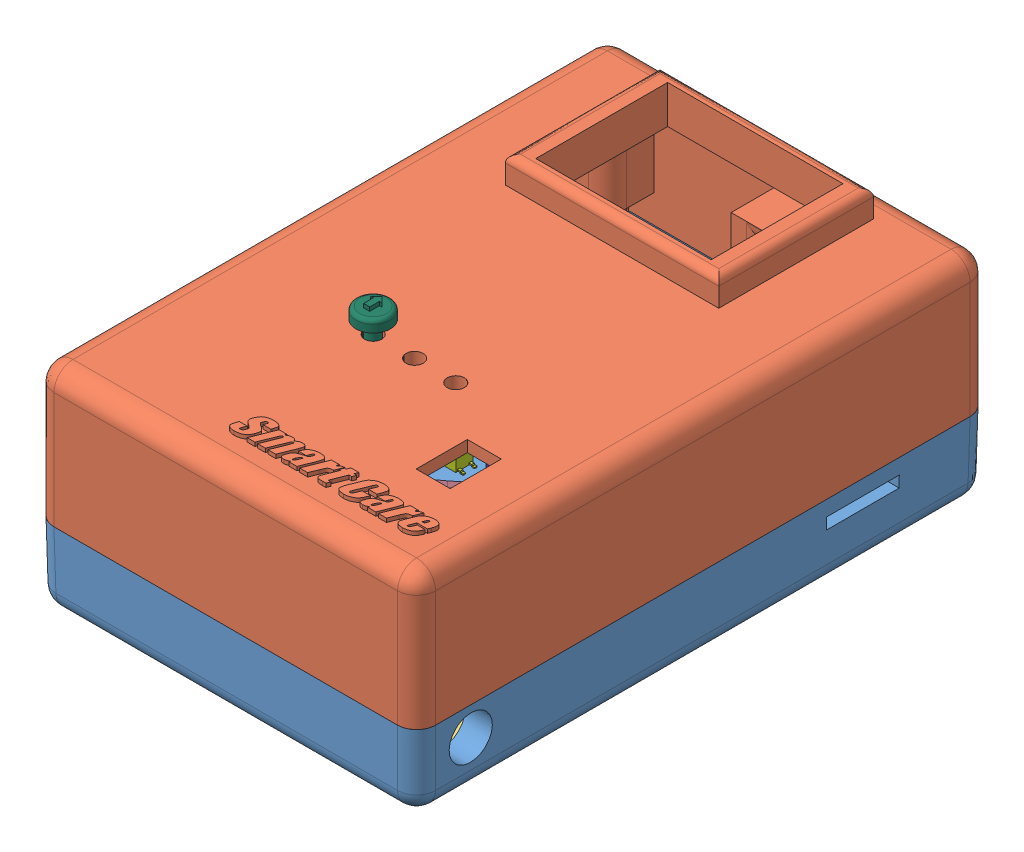
SolidWorks assembly Assem1, configuration Default. Lengths in mm.
Overall size (107.55 70.38 150.1).
258 component instances, 87 part files, 2 mates.
Components (placement in the parent):
- Bottom-1: Bottom [Default] at (52.2963 76.6839 118.1706) size (107.5 43.17 150)
- Top-1: Top [Default] at origin size (100.1 59.21 150.1)
- battery closing-1: battery closing [Default] at origin size (83.47 2 79.99)
- PCB1.step-1: PCB1.step [Default] at (13.8153 94.0015 157.6572) x (1 0 0) z (0 1 0) size (76.65 69.31 14.5)
  - Board.step-1: Board.step [Default] at origin size (76.65 68.06 1.61)
    - Open CASCADE STEP translator 7.5 1.1.1.step-1: Open CASCADE STEP translator 7.5 1.1.1.step [Default] at (0 0 -1.6065) size (76.65 68.06 1.61)
  - SD.step-1: SD.step [Default] at origin size (10.5 3.5 7.2)
    - 6598036848.step-1: 6598036848.step [Default] at (20.962 62.865 0) x (1 0 0) z (0 0 1) size (10.5 3.5 7.2)
      - Body.step-1: Body.step [Default] at origin size (10.5 3.5 4.5)
      - LeadsArray.step-1: LeadsArray.step [Default] at origin size (8 0.5 7.2)
  - Right.step-1: Right.step [Default] at origin size (7.5 4.5 5)
    - 6598039168.step-1: 6598039168.step [Default] at (48.895 14.351 0) x (-1 0 0) z (0 1 0) size (7.5 5 4.5)
  - r9.step-1: r9.step [Default] at origin size (2 1.25 0.6)
    - 6598044208.step-1: 6598044208.step [Default] at (71.247 35.052 0) x (1 0 0) z (0 0 1) size (2 1.25 0.6)
      - solidBody.step-1: solidBody.step [Default] at origin size (2 1.24 0.5)
      - Terminal.step-1: Terminal.step [Default] at origin size (2 1.25 0.6)
      - solidTop.step-1: solidTop.step [Default] at origin size (1.2 1 0.05)
  - r8.step-1: r8.step [Default] at origin size (2 1.25 0.6)
    - 6598044208.step-1: 6598044208.step [Default] at (66.294 35.052 0) x (1 0 0) z (0 0 1) size (2 1.25 0.6)
      - solidBody.step-1: solidBody.step [Default] at origin size (2 1.24 0.5)
      - Terminal.step-1: Terminal.step [Default] at origin size (2 1.25 0.6)
      - solidTop.step-1: solidTop.step [Default] at origin size (1.2 1 0.05)
  - r7.step-1: r7.step [Default] at origin size (2 1.25 0.6)
    - 6598047408.step-1: 6598047408.step [Default] at (23.622 43.688 0) size (2 1.25 0.6)
      - solidBody-0.step-1: solidBody-0.step [Default] at origin size (2 1.24 0.5)
      - Terminal-1.step-1: Terminal-1.step [Default] at origin size (2 1.25 0.6)
      - solidTop-2.step-1: solidTop-2.step [Default] at origin size (1.2 1 0.05)
  - r6.step-1: r6.step [Default] at origin size (2 1.25 0.6)
    - 6598034208.step-1: 6598034208.step [Default] at (18.288 43.688 0) x (-1 0 0) z (0 0 1) size (2 1.25 0.6)
      - solidBody-3.step-1: solidBody-3.step [Default] at origin size (2 1.24 0.5)
      - Terminal-4.step-1: Terminal-4.step [Default] at origin size (2 1.25 0.6)
      - solidTop-5.step-1: solidTop-5.step [Default] at origin size (1.2 1 0.05)
  - r5.step-1: r5.step [Default] at origin size (2 1.25 0.6)
    - 6598034208.step-1: 6598034208.step [Default] at (28.099 39.116 0) x (-1 0 0) z (0 0 1) size (2 1.25 0.6)
      - solidBody-3.step-1: solidBody-3.step [Default] at origin size (2 1.24 0.5)
      - Terminal-4.step-1: Terminal-4.step [Default] at origin size (2 1.25 0.6)
      - solidTop-5.step-1: solidTop-5.step [Default] at origin size (1.2 1 0.05)
  - r4.step-1: r4.step [Default] at origin size (2 1.25 0.6)
    - 6598034208.step-1: 6598034208.step [Default] at (50.673 49.149 -1.6065) x (-1 0 0) z (0 0 -1) size (2 1.25 0.6)
      - solidBody-3.step-1: solidBody-3.step [Default] at origin size (2 1.24 0.5)
      - Terminal-4.step-1: Terminal-4.step [Default] at origin size (2 1.25 0.6)
      - solidTop-5.step-1: solidTop-5.step [Default] at origin size (1.2 1 0.05)
  - r3.step-1: r3.step [Default] at origin size (2 1.25 0.6)
    - 6598034208.step-1: 6598034208.step [Default] at (50.673 51.308 -1.6065) x (-1 0 0) z (0 0 -1) size (2 1.25 0.6)
      - solidBody-3.step-1: solidBody-3.step [Default] at origin size (2 1.24 0.5)
      - Terminal-4.step-1: Terminal-4.step [Default] at origin size (2 1.25 0.6)
      - solidTop-5.step-1: solidTop-5.step [Default] at origin size (1.2 1 0.05)
  - r2.step-1: r2.step [Default] at origin size (2 1.25 0.6)
    - 6598034208.step-1: 6598034208.step [Default] at (50.673 53.594 -1.6065) x (-1 0 0) z (0 0 -1) size (2 1.25 0.6)
      - solidBody-3.step-1: solidBody-3.step [Default] at origin size (2 1.24 0.5)
      - Terminal-4.step-1: Terminal-4.step [Default] at origin size (2 1.25 0.6)
      - solidTop-5.step-1: solidTop-5.step [Default] at origin size (1.2 1 0.05)
  - r1.step-1: r1.step [Default] at origin size (2 1.25 0.6)
    - 6598034208.step-1: 6598034208.step [Default] at (62.611 46.355 -1.6065) x (-1 0 0) z (0 0 -1) size (2 1.25 0.6)
      - solidBody-3.step-1: solidBody-3.step [Default] at origin size (2 1.24 0.5)
      - Terminal-4.step-1: Terminal-4.step [Default] at origin size (2 1.25 0.6)
      - solidTop-5.step-1: solidTop-5.step [Default] at origin size (1.2 1 0.05)
  - Power.step-1: Power.step [Default] at origin size (9.4 14.4 14.5)
    - 6598038208.step-1: 6598038208.step [Default] at (60.325 22.564 5.5) x (0 -1 0) z (-1 0 0) size (14.4 14.5 9.4)
  - On_Off.step-1: On_Off.step [Default] at origin size (5.9 4.5 9.4)
    - 6598040288.step-1: 6598040288.step [Default] at (50.562 28.406 2.91) x (1 0 0) z (0 -1 0) size (5.9 9.4 4.5)
  - Left.step-1: Left.step [Default] at origin size (7.5 4.5 5)
    - 6598039168.step-1: 6598039168.step [Default] at (27.095 14.502 0) x (-1 0 0) z (0 1 0) size (7.5 5 4.5)
  - J1.step-1: J1.step [Default] at origin size (6.75 8.95 4.17)
    - Conn_Molex_2171790001_eec.step-1: Conn_Molex_2171790001_eec.step [Default] at (73.406 43.815 0) x (0 1 0) z (0 0 1) size (8.95 6.75 4.17)
      - A1.step-1: A1.step [Default] at (-0.0001 0.125 1.5815) x (-1 0 0) z (0 1 0) size (8.95 4.17 6.75)
        - 1.step-1: 1.step [Default] at origin size (5.77 0.7 2.37)
        - 2.step-1: 2.step [Default] at origin size (6.69 0.16 2.46)
        - 3.step-1: 3.step [Default] at origin size (6.85 0.12 0.59)
        - 4.step-1: 4.step [Default] at origin size (3.83 0.9 0.61)
        - 5.step-1: 5.step [Default] at origin size (8.29 2.9 0.65)
        - 6.step-1: 6.step [Default] at origin size (8.29 2.62 0.59)
        - 7.step-1: 7.step [Default] at origin size (4.77 2.56 0.5)
        - 8.step-1: 8.step [Default] at origin size (8.29 2.49 5.77)
        - 9.step-1: 9.step [Default] at origin size (8.95 4.17 6.5)
      - Notch.step-1: Notch.step [Default] at (2.989 3.252 0.0996) x (1 0 0) z (0 -1 0) size (0.16 0.12 0)
      - Molex.step-1: Molex.step [Default] at (0.4529 0.8873 3.359) size (1.82 0.45 0)
  - IC2.step-1: IC2.step [Default] at origin size (18 25.5 3.25)
    - 6598038368.step-1: 6598038368.step [Default] at (38.454 56.936 0) x (1 0 0) z (0 -1 0) size (18 3.25 25.5)
  - Enter.step-1: Enter.step [Default] at origin size (7.5 4.5 5)
    - 6598039168.step-1: 6598039168.step [Default] at (37.973 14.478 0) x (-1 0 0) z (0 1 0) size (7.5 5 4.5)
  - EN.step-1: EN.step [Default] at origin size (4.5 7.5 5)
    - 6598042848.step-1: 6598042848.step [Default] at (22.479 52.324 0) x (0 1 0) z (1 0 0) size (7.5 5 4.5)
  - ECG.step-1: ECG.step [Default] at origin size (10.5 3.5 7.2)
    - 6598036848.step-1: 6598036848.step [Default] at (62.158 63.627 0) x (1 0 0) z (0 0 1) size (10.5 3.5 7.2)
      - Body.step-1: Body.step [Default] at origin size (10.5 3.5 4.5)
      - LeadsArray.step-1: LeadsArray.step [Default] at origin size (8 0.5 7.2)
  - TFT.step-1: TFT.step [Default] at origin size (6.4 22.5 12.2)
    - 6598036528.step-1: 6598036528.step [Default] at (7.493 54.838 0) x (0 1 0) z (0 0 1) size (22.5 6.4 12.2)
      - Body-6.step-1: Body-6.step [Default] at origin size (22.5 6.4 8.8)
      - LeadsArray-7.step-1: LeadsArray-7.step [Default] at origin size (18.1 0.6 12.2)
  - D4.step-1: D4.step [Default] at origin size (1.07 0.68 0.43)
    - 6598042608.step-1: 6598042608.step [Default] at (66.873 37.973 0.01) x (1 0 0) z (0 -1 0) size (1.07 0.43 0.68)
  - D3.step-1: D3.step [Default] at origin size (1.07 0.68 0.43)
    - 6598042608.step-1: 6598042608.step [Default] at (66.802 40.64 0.01) x (1 0 0) z (0 -1 0) size (1.07 0.43 0.68)
  - D2.step-1: D2.step [Default] at origin size (1.07 0.68 0.43)
    - 6598042608.step-1: 6598042608.step [Default] at (66.802 42.926 0.01) x (1 0 0) z (0 -1 0) size (1.07 0.43 0.68)
  - D1.step-1: D1.step [Default] at origin size (1.07 0.68 0.43)
    - 6598042608.step-1: 6598042608.step [Default] at (66.675 45.085 0.01) x (1 0 0) z (0 -1 0) size (1.07 0.43 0.68)
  - c20.step-1: c20.step [Default] at origin size (2 1.25 1.4)
    - 6598033648.step-1: 6598033648.step [Default] at (46.99 39.497 0) x (-1 0 0) z (0 0 1) size (2 1.25 1.4)
      - Fillet1.step-1: Fillet1.step [Default] at origin size (0.5 1.25 1.4)
      - Fillet2.step-1: Fillet2.step [Default] at origin size (0.5 1.25 1.4)
      - body2.step-1: body2.step [Default] at origin size (1 1.22 1.37)
  - c19.step-1: c19.step [Default] at origin size (2 1.25 1.4)
    - 6598033648.step-1: 6598033648.step [Default] at (32.385 7.874 0) x (-1 0 0) z (0 0 1) size (2 1.25 1.4)
      - Fillet1.step-1: Fillet1.step [Default] at origin size (0.5 1.25 1.4)
      - Fillet2.step-1: Fillet2.step [Default] at origin size (0.5 1.25 1.4)
      - body2.step-1: body2.step [Default] at origin size (1 1.22 1.37)
  - c18.step-1: c18.step [Default] at origin size (2 1.25 1.4)
    - 6598033648.step-1: 6598033648.step [Default] at (44.069 7.874 0) x (-1 0 0) z (0 0 1) size (2 1.25 1.4)
      - Fillet1.step-1: Fillet1.step [Default] at origin size (0.5 1.25 1.4)
      - Fillet2.step-1: Fillet2.step [Default] at origin size (0.5 1.25 1.4)
      - body2.step-1: body2.step [Default] at origin size (1 1.22 1.37)
  - c17.step-1: c17.step [Default] at origin size (2 1.25 1.4)
    - 6598033648.step-1: 6598033648.step [Default] at (38.354 8.001 0) x (-1 0 0) z (0 0 1) size (2 1.25 1.4)
      - Fillet1.step-1: Fillet1.step [Default] at origin size (0.5 1.25 1.4)
      - Fillet2.step-1: Fillet2.step [Default] at origin size (0.5 1.25 1.4)
      - body2.step-1: body2.step [Default] at origin size (1 1.22 1.37)
  - c16.step-1: c16.step [Default] at origin size (2 1.25 1.4)
    - 6598043008.step-1: 6598043008.step [Default] at (16.383 54.229 0) x (1 0 0) z (0 0 1) size (2 1.25 1.4)
      - Fillet1-8.step-1: Fillet1-8.step [Default] at origin size (0.5 1.25 1.4)
      - Fillet2-9.step-1: Fillet2-9.step [Default] at origin size (0.5 1.25 1.4)
      - body2-10.step-1: body2-10.step [Default] at origin size (1 1.22 1.37)
  - c15.step-1: c15.step [Default] at origin size (2 1.25 1.4)
    - 6598043008.step-1: 6598043008.step [Default] at (31.28 21.717 0) x (1 0 0) z (0 0 1) size (2 1.25 1.4)
      - Fillet1-8.step-1: Fillet1-8.step [Default] at origin size (0.5 1.25 1.4)
      - Fillet2-9.step-1: Fillet2-9.step [Default] at origin size (0.5 1.25 1.4)
      - body2-10.step-1: body2-10.step [Default] at origin size (1 1.22 1.37)
  - c14.step-1: c14.step [Default] at origin size (2 1.25 1.4)
    - 6598043008.step-1: 6598043008.step [Default] at (26.454 21.463 0) x (1 0 0) z (0 0 1) size (2 1.25 1.4)
      - Fillet1-8.step-1: Fillet1-8.step [Default] at origin size (0.5 1.25 1.4)
      - Fillet2-9.step-1: Fillet2-9.step [Default] at origin size (0.5 1.25 1.4)
      - body2-10.step-1: body2-10.step [Default] at origin size (1 1.22 1.37)
  - c13.step-1: c13.step [Default] at origin size (2 1.25 1.4)
    - 6598033648.step-1: 6598033648.step [Default] at (42.291 22.098 0) x (-1 0 0) z (0 0 1) size (2 1.25 1.4)
      - Fillet1.step-1: Fillet1.step [Default] at origin size (0.5 1.25 1.4)
      - Fillet2.step-1: Fillet2.step [Default] at origin size (0.5 1.25 1.4)
      - body2.step-1: body2.step [Default] at origin size (1 1.22 1.37)
  - c12.step-1: c12.step [Default] at origin size (1.25 2 1.4)
    - 6598039248.step-1: 6598039248.step [Default] at (33.909 29.68 0) x (0 -1 0) z (0 0 1) size (2 1.25 1.4)
      - Fillet1-11.step-1: Fillet1-11.step [Default] at origin size (0.5 1.25 1.4)
      - Fillet2-12.step-1: Fillet2-12.step [Default] at origin size (0.5 1.25 1.4)
      - body2-13.step-1: body2-13.step [Default] at origin size (1 1.22 1.37)
  - c11.step-1: c11.step [Default] at origin size (2 1.25 1.4)
    - 6598043008.step-1: 6598043008.step [Default] at (37.503 21.844 0) x (1 0 0) z (0 0 1) size (2 1.25 1.4)
      - Fillet1-8.step-1: Fillet1-8.step [Default] at origin size (0.5 1.25 1.4)
      - Fillet2-9.step-1: Fillet2-9.step [Default] at origin size (0.5 1.25 1.4)
      - body2-10.step-1: body2-10.step [Default] at origin size (1 1.22 1.37)
  - c10.step-1: c10.step [Default] at origin size (2 1.25 1.4)
    - 6598033648.step-1: 6598033648.step [Default] at (42.075 39.497 0) x (-1 0 0) z (0 0 1) size (2 1.25 1.4)
      - Fillet1.step-1: Fillet1.step [Default] at origin size (0.5 1.25 1.4)
      - Fillet2.step-1: Fillet2.step [Default] at origin size (0.5 1.25 1.4)
      - body2.step-1: body2.step [Default] at origin size (1 1.22 1.37)
  - c9.step-1: c9.step [Default] at origin size (2 1.25 1.4)
    - 6598040608.step-1: 6598040608.step [Default] at (37.211 39.116 0) size (2 1.25 1.4)
      - Fillet1-14.step-1: Fillet1-14.step [Default] at origin size (0.5 1.25 1.4)
      - Fillet2-15.step-1: Fillet2-15.step [Default] at origin size (0.5 1.25 1.4)
      - body2-16.step-1: body2-16.step [Default] at origin size (1 1.22 1.37)
  - c8.step-1: c8.step [Default] at origin size (2 1.25 1.4)
    - 6598033648.step-1: 6598033648.step [Default] at (32.893 39.116 0) x (-1 0 0) z (0 0 1) size (2 1.25 1.4)
      - Fillet1.step-1: Fillet1.step [Default] at origin size (0.5 1.25 1.4)
      - Fillet2.step-1: Fillet2.step [Default] at origin size (0.5 1.25 1.4)
      - body2.step-1: body2.step [Default] at origin size (1 1.22 1.37)
  - c7.step-1: c7.step [Default] at origin size (2 1.25 1.4)
    - 6598033648.step-1: 6598033648.step [Default] at (50.635 56.007 -1.6065) x (-1 0 0) z (0 0 -1) size (2 1.25 1.4)
      - Fillet1.step-1: Fillet1.step [Default] at origin size (0.5 1.25 1.4)
      - Fillet2.step-1: Fillet2.step [Default] at origin size (0.5 1.25 1.4)
      - body2.step-1: body2.step [Default] at origin size (1 1.22 1.37)
  - c6.step-1: c6.step [Default] at origin size (2 1.25 1.4)
    - 6598033648.step-1: 6598033648.step [Default] at (50.673 58.293 -1.6065) x (-1 0 0) z (0 0 -1) size (2 1.25 1.4)
      - Fillet1.step-1: Fillet1.step [Default] at origin size (0.5 1.25 1.4)
      - Fillet2.step-1: Fillet2.step [Default] at origin size (0.5 1.25 1.4)
      - body2.step-1: body2.step [Default] at origin size (1 1.22 1.37)
  - c5.step-1: c5.step [Default] at origin size (2 1.25 1.4)
    - 6598033648.step-1: 6598033648.step [Default] at (62.776 48.641 -1.6065) x (-1 0 0) z (0 0 -1) size (2 1.25 1.4)
      - Fillet1.step-1: Fillet1.step [Default] at origin size (0.5 1.25 1.4)
      - Fillet2.step-1: Fillet2.step [Default] at origin size (0.5 1.25 1.4)
      - body2.step-1: body2.step [Default] at origin size (1 1.22 1.37)
  - c4.step-1: c4.step [Default] at origin size (2 1.25 1.4)
    - 6598033648.step-1: 6598033648.step [Default] at (62.865 50.8 -1.6065) x (-1 0 0) z (0 0 -1) size (2 1.25 1.4)
      - Fillet1.step-1: Fillet1.step [Default] at origin size (0.5 1.25 1.4)
      - Fillet2.step-1: Fillet2.step [Default] at origin size (0.5 1.25 1.4)
      - body2.step-1: body2.step [Default] at origin size (1 1.22 1.37)
  - c3.step-1: c3.step [Default] at origin size (2 1.25 1.4)
    - 6598033648.step-1: 6598033648.step [Default] at (62.865 53.086 -1.6065) x (-1 0 0) z (0 0 -1) size (2 1.25 1.4)
      - Fillet1.step-1: Fillet1.step [Default] at origin size (0.5 1.25 1.4)
      - Fillet2.step-1: Fillet2.step [Default] at origin size (0.5 1.25 1.4)
      - body2.step-1: body2.step [Default] at origin size (1 1.22 1.37)
  - c2.step-1: c2.step [Default] at origin size (2 1.25 1.4)
    - 6598033648.step-1: 6598033648.step [Default] at (62.992 55.626 -1.6065) x (-1 0 0) z (0 0 -1) size (2 1.25 1.4)
      - Fillet1.step-1: Fillet1.step [Default] at origin size (0.5 1.25 1.4)
      - Fillet2.step-1: Fillet2.step [Default] at origin size (0.5 1.25 1.4)
      - body2.step-1: body2.step [Default] at origin size (1 1.22 1.37)
  - c1.step-1: c1.step [Default] at origin size (2 1.25 1.4)
    - 6598033648.step-1: 6598033648.step [Default] at (63.03 58.293 -1.6065) x (-1 0 0) z (0 0 -1) size (2 1.25 1.4)
      - Fillet1.step-1: Fillet1.step [Default] at origin size (0.5 1.25 1.4)
      - Fillet2.step-1: Fillet2.step [Default] at origin size (0.5 1.25 1.4)
      - body2.step-1: body2.step [Default] at origin size (1 1.22 1.37)
  - Boot.step-1: Boot.step [Default] at origin size (7.5 4.5 5)
    - 6598039168.step-1: 6598039168.step [Default] at (56.007 43.561 0) x (-1 0 0) z (0 1 0) size (7.5 5 4.5)
  - ADS1293.step-1: ADS1293.step [Default] at origin size (5 5 0.8)
    - 6598042528.step-1: 6598042528.step [Default] at (57.785 57.023 0) x (0 -1 0) z (0 0 1) size (5 5 0.8)
      - FRAME-RSG0028A.step-1: FRAME-RSG0028A.step [Default] x (1 0 0) z (0 -1 0) size (5 0.2 5)
        - Open CASCADE STEP translator 7.5 1.47.1.2.1.step-1: Open CASCADE STEP translator 7.5 1.47.1.2.1.step [Default] at origin size (3.8 0.2 3.8)
        - Open CASCADE STEP translator 7.5 1.47.1.2.2.step-1: Open CASCADE STEP translator 7.5 1.47.1.2.2.step [Default] at origin size (0.4 0.1 0.25)
        - Open CASCADE STEP translator 7.5 1.47.1.2.3.step-1: Open CASCADE STEP translator 7.5 1.47.1.2.3.step [Default] at origin size (0.25 0.1 0.4)
        - Open CASCADE STEP translator 7.5 1.47.1.2.4.step-1: Open CASCADE STEP translator 7.5 1.47.1.2.4.step [Default] at origin size (0.25 0.1 0.4)
        - Open CASCADE STEP translator 7.5 1.47.1.2.5.step-1: Open CASCADE STEP translator 7.5 1.47.1.2.5.step [Default] at origin size (0.25 0.1 0.4)
        - Open CASCADE STEP translator 7.5 1.47.1.2.6.step-1: Open CASCADE STEP translator 7.5 1.47.1.2.6.step [Default] at origin size (0.25 0.1 0.4)
        - Open CASCADE STEP translator 7.5 1.47.1.2.7.step-1: Open CASCADE STEP translator 7.5 1.47.1.2.7.step [Default] at origin size (0.25 0.1 0.4)
        - Open CASCADE STEP translator 7.5 1.47.1.2.8.step-1: Open CASCADE STEP translator 7.5 1.47.1.2.8.step [Default] at origin size (0.25 0.1 0.4)
        - Open CASCADE STEP translator 7.5 1.47.1.2.9.step-1: Open CASCADE STEP translator 7.5 1.47.1.2.9.step [Default] at origin size (0.25 0.1 0.4)
        - Open CASCADE STEP translator 7.5 1.47.1.2.10.step-1: Open CASCADE STEP translator 7.5 1.47.1.2.10.step [Default] at origin size (0.25 0.1 0.4)
        - Open CASCADE STEP translator 7.5 1.47.1.2.11.step-1: Open CASCADE STEP translator 7.5 1.47.1.2.11.step [Default] at origin size (0.25 0.1 0.4)
        - Open CASCADE STEP translator 7.5 1.47.1.2.12.step-1: Open CASCADE STEP translator 7.5 1.47.1.2.12.step [Default] at origin size (0.25 0.1 0.4)
        - Open CASCADE STEP translator 7.5 1.47.1.2.13.step-1: Open CASCADE STEP translator 7.5 1.47.1.2.13.step [Default] at origin size (0.4 0.1 0.25)
        - Open CASCADE STEP translator 7.5 1.47.1.2.14.step-1: Open CASCADE STEP translator 7.5 1.47.1.2.14.step [Default] at origin size (0.4 0.1 0.25)
        - Open CASCADE STEP translator 7.5 1.47.1.2.15.step-1: Open CASCADE STEP translator 7.5 1.47.1.2.15.step [Default] at origin size (0.4 0.1 0.25)
        - Open CASCADE STEP translator 7.5 1.47.1.2.16.step-1: Open CASCADE STEP translator 7.5 1.47.1.2.16.step [Default] at origin size (0.4 0.1 0.25)
        - Open CASCADE STEP translator 7.5 1.47.1.2.17.step-1: Open CASCADE STEP translator 7.5 1.47.1.2.17.step [Default] at origin size (0.4 0.1 0.25)
        - Open CASCADE STEP translator 7.5 1.47.1.2.18.step-1: Open CASCADE STEP translator 7.5 1.47.1.2.18.step [Default] at origin size (0.4 0.1 0.25)
        - Open CASCADE STEP translator 7.5 1.47.1.2.19.step-1: Open CASCADE STEP translator 7.5 1.47.1.2.19.step [Default] at origin size (0.4 0.1 0.25)
        - Open CASCADE STEP translator 7.5 1.47.1.2.20.step-1: Open CASCADE STEP translator 7.5 1.47.1.2.20.step [Default] at origin size (0.4 0.1 0.25)
        - Open CASCADE STEP translator 7.5 1.47.1.2.21.step-1: Open CASCADE STEP translator 7.5 1.47.1.2.21.step [Default] at origin size (0.4 0.1 0.25)
        - Open CASCADE STEP translator 7.5 1.47.1.2.22.step-1: Open CASCADE STEP translator 7.5 1.47.1.2.22.step [Default] at origin size (0.4 0.1 0.25)
        - Open CASCADE STEP translator 7.5 1.47.1.2.23.step-1: Open CASCADE STEP translator 7.5 1.47.1.2.23.step [Default] at origin size (0.4 0.1 0.25)
        - Open CASCADE STEP translator 7.5 1.47.1.2.24.step-1: Open CASCADE STEP translator 7.5 1.47.1.2.24.step [Default] at origin size (0.25 0.1 0.4)
        - Open CASCADE STEP translator 7.5 1.47.1.2.25.step-1: Open CASCADE STEP translator 7.5 1.47.1.2.25.step [Default] at origin size (0.4 0.1 0.25)
        - Open CASCADE STEP translator 7.5 1.47.1.2.26.step-1: Open CASCADE STEP translator 7.5 1.47.1.2.26.step [Default] at origin size (0.25 0.1 0.4)
        - Open CASCADE STEP translator 7.5 1.47.1.2.27.step-1: Open CASCADE STEP translator 7.5 1.47.1.2.27.step [Default] at origin size (0.4 0.1 0.25)
        - Open CASCADE STEP translator 7.5 1.47.1.2.28.step-1: Open CASCADE STEP translator 7.5 1.47.1.2.28.step [Default] at origin size (0.4 0.1 0.4)
        - Open CASCADE STEP translator 7.5 1.47.1.2.29.step-1: Open CASCADE STEP translator 7.5 1.47.1.2.29.step [Default] at origin size (0.4 0.1 0.4)
        - Open CASCADE STEP translator 7.5 1.47.1.2.30.step-1: Open CASCADE STEP translator 7.5 1.47.1.2.30.step [Default] at origin size (0.4 0.1 0.4)
        - Open CASCADE STEP translator 7.5 1.47.1.2.31.step-1: Open CASCADE STEP translator 7.5 1.47.1.2.31.step [Default] at origin size (0.4 0.1 0.4)
        - Open CASCADE STEP translator 7.5 1.47.1.2.32.step-1: Open CASCADE STEP translator 7.5 1.47.1.2.32.step [Default] at origin size (0.25 0.1 0.4)
        - Open CASCADE STEP translator 7.5 1.47.1.2.33.step-1: Open CASCADE STEP translator 7.5 1.47.1.2.33.step [Default] at origin size (0.25 0.1 0.4)
      - BODY-QFN.step-1: BODY-QFN.step [Default] at (0 0 0.025) x (1 0 0) z (0 -1 0) size (5 0.78 5)
  - 5v Reg.step-1: 5v Reg.step [Default] at origin size (6.5 7 1.68)
    - 6598046528.step-1: 6598046528.step [Default] at (40.513 30.607 0) x (0 1 0) z (0 0 1) size (7 6.5 1.68)
      - BODY-SOT.step-1: BODY-SOT.step [Default] at (0 0 0.7874) x (0 -1 0) z (-1 0 0) size (6.5 1.6 3.5)
      - LEAD-SOT.step-1: LEAD-SOT.step [Default] at (-2.7498 -2.2438 0.25) x (0 -1 0) z (-1 0 0) size (0.75 0.79 1.75)
      - LEAD-SOT.step-2: LEAD-SOT.step [Default] at (-2.7498 0.0562 0.25) x (0 -1 0) z (-1 0 0) size (0.75 0.79 1.75)
      - LEAD-SOT.step-3: LEAD-SOT.step [Default] at (-2.7498 2.3562 0.25) x (0 -1 0) z (-1 0 0) size (0.75 0.79 1.75)
      - LEAD-SOT-WIDE.step-1: LEAD-SOT-WIDE.step [Default] at (2.7498 0.0026 0.25) x (0 1 0) z (1 0 0) size (3 0.79 1.75)
  - 4.096MHz.step-1: 4.096MHz.step [Default] at origin size (14.6 4.8 4.4)
    - 6598034928.step-1: 6598034928.step [Default] at (67.361 52.578 0) x (-1 0 0) z (0 0 1) size (14.6 4.8 4.4)
      - Body-17.step-1: Body-17.step [Default] at (0 0 0.1) size (11.4 4.8 4.3)
      - Pins.step-1: Pins.step [Default] at origin size (14.6 1.6 0.1)
  - 3.3v Reg.step-1: 3.3v Reg.step [Default] at origin size (6.5 7 1.68)
    - 6598046528.step-1: 6598046528.step [Default] at (28.307 30.024 0) x (0 1 0) z (0 0 1) size (7 6.5 1.68)
      - BODY-SOT.step-1: BODY-SOT.step [Default] at (0 0 0.7874) x (0 -1 0) z (-1 0 0) size (6.5 1.6 3.5)
      - LEAD-SOT.step-1: LEAD-SOT.step [Default] at (-2.7498 -2.2438 0.25) x (0 -1 0) z (-1 0 0) size (0.75 0.79 1.75)
      - LEAD-SOT.step-2: LEAD-SOT.step [Default] at (-2.7498 0.0562 0.25) x (0 -1 0) z (-1 0 0) size (0.75 0.79 1.75)
      - LEAD-SOT.step-3: LEAD-SOT.step [Default] at (-2.7498 2.3562 0.25) x (0 -1 0) z (-1 0 0) size (0.75 0.79 1.75)
      - LEAD-SOT-WIDE.step-1: LEAD-SOT-WIDE.step [Default] at (2.7498 0.0026 0.25) x (0 1 0) z (1 0 0) size (3 0.79 1.75)
- Button part-1: Button part [Default] at origin size (9 2.2 9)
- button top1-1: button top1 [Default] at origin size (9 18 9)
Mates (geometry in assembly coordinates):
- Concentric1: concentric anti-aligned: circle of Bottom-1; circle of PCB1.step-1/Board.step-1/Open CASCADE STEP translator 7.5 1.1.1.step-1
- Coincident2: coincident aligned: plane of Bottom-1 through (52.2963 92.395 154.3552) normal (0 1 0); circle of PCB1.step-1/Board.step-1/Open CASCADE STEP translator 7.5 1.1.1.step-1
